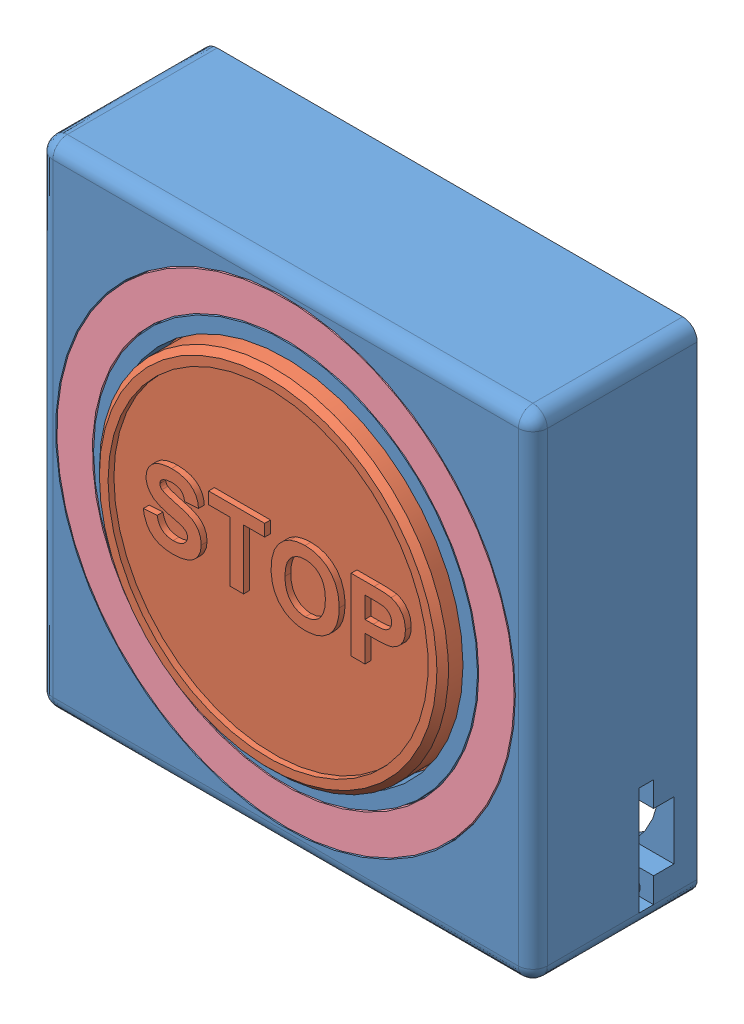
SolidWorks assembly Assemblage1, configuration Défaut. Lengths in mm.
Overall size (100.6 100.6 31.25).
4 component instances, 4 part files, 8 mates.
Components (placement in the parent):
- front-1: front [Défaut] at (-6.0557 7.2775 80) size (85 85 28.25)
- Button-1: Button [Défaut] at (-6.0557 7.2775 80) size (69.63 70 10.75)
- keypad-1: keypad [Défaut] at (-31.0557 -24.2225 66.85) x (1 0 0) z (0 -1 0) size (51 18.92 69.25)
- diffsuer-1: diffsuer [Défaut] at (-6.0557 7.2775 84) x (0.339153 0.940731 0) z (0 0 1) size (78.6 78.6 1)
Mates (geometry in assembly coordinates):
- Coaxiale1: concentric anti-aligned: cylinder of front-1 through (-6.0557 7.2775 80) axis (0 0 1) radius 30.5; cylinder of Button-1 through (-6.0557 7.2775 87) axis (0 0 -1) radius 30
- Parallèle1: parallel anti-aligned: plane of front-1 through (-48.5557 10.5275 77) normal (0 1 0); plane of Button-1 through (-38.3557 10.8775 79) normal (0 -1 0)
- Coïncidente2: coincident anti-aligned: plane of front-1 through (-6.0557 7.2775 80) normal (0 0 -1); plane of Button-1 through (-6.0557 7.2775 80) normal (0 0 1)
- Coïncidente9: coincident anti-aligned: plane of front-1 through (17.4443 33.8857 70) normal (-1 0 0); plane of keypad-1 through (17.4443 -18.2225 75) normal (1 0 0)
- Coïncidente10: coincident anti-aligned: plane of front-1 through (17.4443 36.2775 70) normal (0 -1 0); plane of keypad-1 through (14.9443 36.2775 75) normal (0 1 0)
- Coïncidente11: coincident anti-aligned: plane of front-1 through (-6.0557 7.2775 70) normal (0 0 -1); plane of keypad-1 through (-31.0557 -24.2225 70) normal (0 0 1)
- Coaxiale2: concentric: cylinder of front-1 through (-6.0557 7.2775 81.5) axis (0 0 1) radius 33; cylinder of diffsuer-1 through (-6.0557 7.2775 85) axis (0 0 -1) radius 33.2
- Coïncidente12: coincident aligned: plane of front-1 through (-6.0557 7.2775 85) normal (0 0 1); plane of diffsuer-1 through (-6.0557 7.2775 85) normal (0 0 1)
